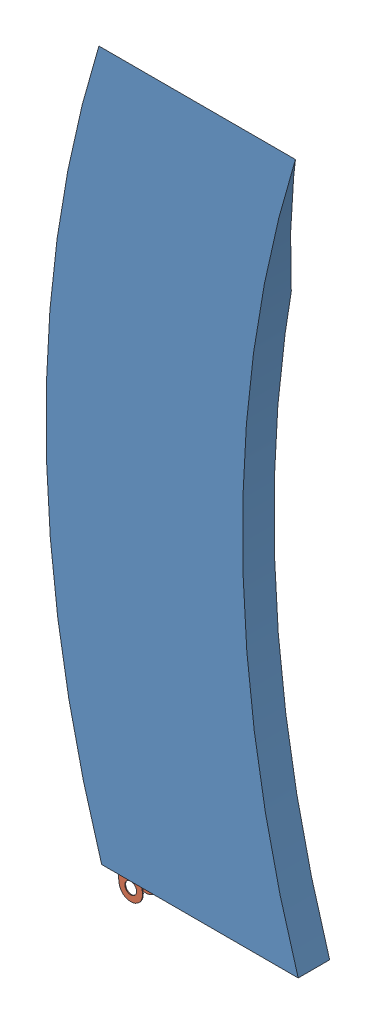
SolidWorks assembly 薄膜开关1, configuration 默认. Lengths in mm.
Overall size (32.56 93.77 4).
3 component instances, 2 part files, 8 mates.
Components (placement in the parent):
- 橡胶片-1: 橡胶片 [默认] at (-25.8828 -41.0871 88.5) size (32.09 90 4)
- 引脚-1: 引脚 [默认] at (-27.9457 1.9101 91.4) x (0.994382 0.105853 0) z (0 0 1) size (10 51.5 0.1)
- 引脚-2: 引脚 [默认] at (-27.9457 1.9101 89.5) x (0.994382 0.105853 0) z (0 0 1) size (10 51.5 0.1)
Mates (geometry in assembly coordinates):
- 重合1: coincident anti-aligned: plane of 橡胶片-1 through (-13.8828 -21.0871 91.5) normal (0 0 -1); plane of 引脚-1 through (-27.9457 1.9101 91.5) normal (0 0 1)
- 相切1: tangent aligned: cylinder of 橡胶片-1 through (117.0317 4.4702 92.5) axis (0 0 -1) radius 150; cylinder of 引脚-1 through (-27.9457 1.9101 91.5) axis (0 0 -1) radius 5
- 距离4: distance = 1 mm anti-aligned: plane of 橡胶片-1 through (-25.8828 -41.0871 92.5) normal (0 -1 0); cylinder of 引脚-1 through (-23.1823 -42.8371 91.5) axis (0 0 -1) radius 0.75
- 距离1: distance = 1 mm: line of 橡胶片-1 through (-25.8828 -41.0871 92.5) axis (0 0 -1); plane of 引脚-1 through (-28.9324 -2.9916 91.5) normal (-0.994382 -0.105853 0)
- 重合4: coincident anti-aligned: plane of 橡胶片-1 through (-13.8828 28.9129 89.5) normal (0 0 1); plane of 引脚-2 through (-27.9457 1.9101 89.5) normal (0 0 -1)
- 相切7: tangent aligned: cylinder of 橡胶片-1 through (117.0317 4.4702 92.5) axis (0 0 -1) radius 150; cylinder of 引脚-2 through (-27.9457 1.9101 89.6) axis (0 0 -1) radius 5
- 距离3: distance = 1 mm anti-aligned: plane of 橡胶片-1 through (-25.8828 -41.0871 92.5) normal (0 -1 0); cylinder of 引脚-2 through (-23.1823 -42.8371 89.6) axis (0 0 -1) radius 0.75
- 距离2: distance = 1 mm: line of 橡胶片-1 through (-25.8828 -41.0871 92.5) axis (0 0 -1); plane of 引脚-2 through (-28.9324 -2.9916 89.6) normal (-0.994382 -0.105853 0)
